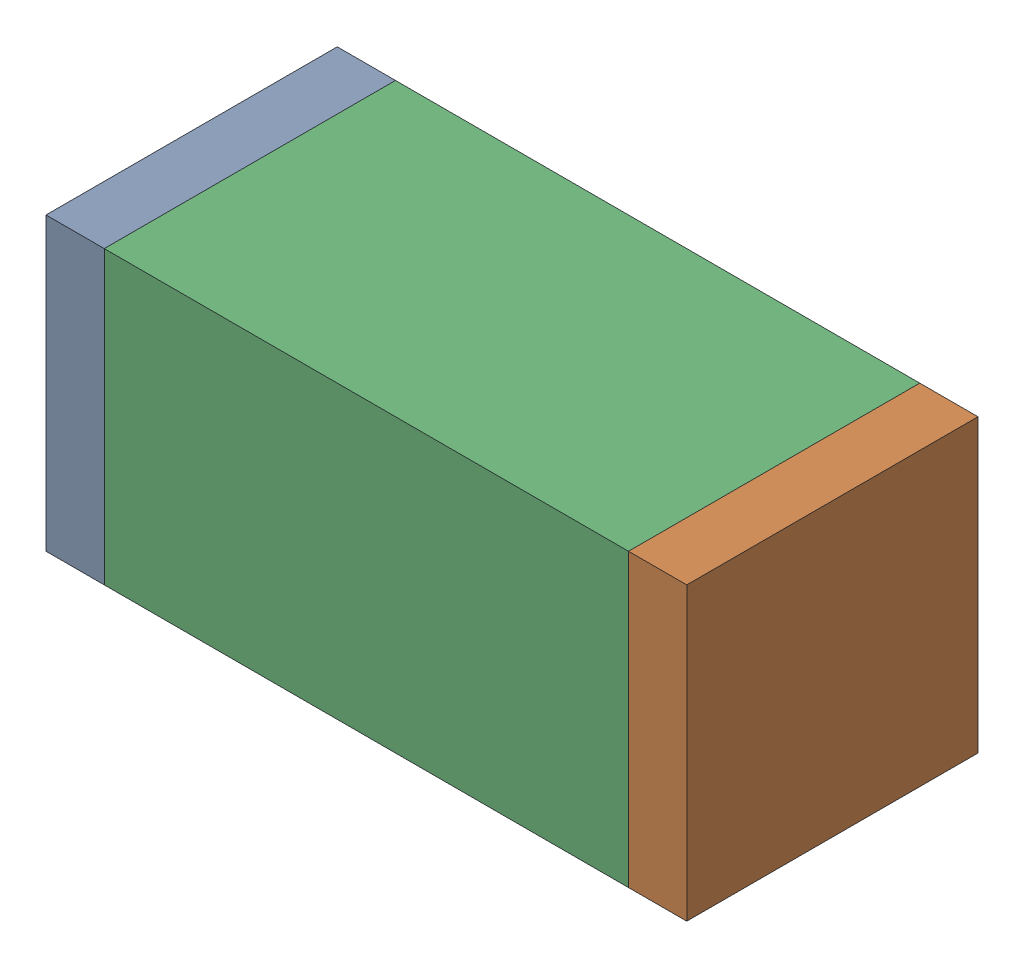
SolidWorks assembly C64, configuration Default. Lengths in mm.
Overall size (1.1 0.5 0.5).
6 component instances, 2 part files, 0 mates.
Components (placement in the parent):
- 810156080-1: 810156080 [Default] at (119.1 54.4 0) size (0.1 0.5 0.5)
  - Extruded_5-1: Extruded_5 [Default] at origin size (0.1 0.5 0.5)
- 810156080-2: 810156080 [Default] at (120.1 54.4 0) size (0.1 0.5 0.5)
  - Extruded_5-1: Extruded_5 [Default] at origin size (0.1 0.5 0.5)
- 836749680-1: 836749680 [Default] at (119.6 54.4 0) size (0.9 0.5 0.5)
  - Extruded_4-1: Extruded_4 [Default] at origin size (0.9 0.5 0.5)
